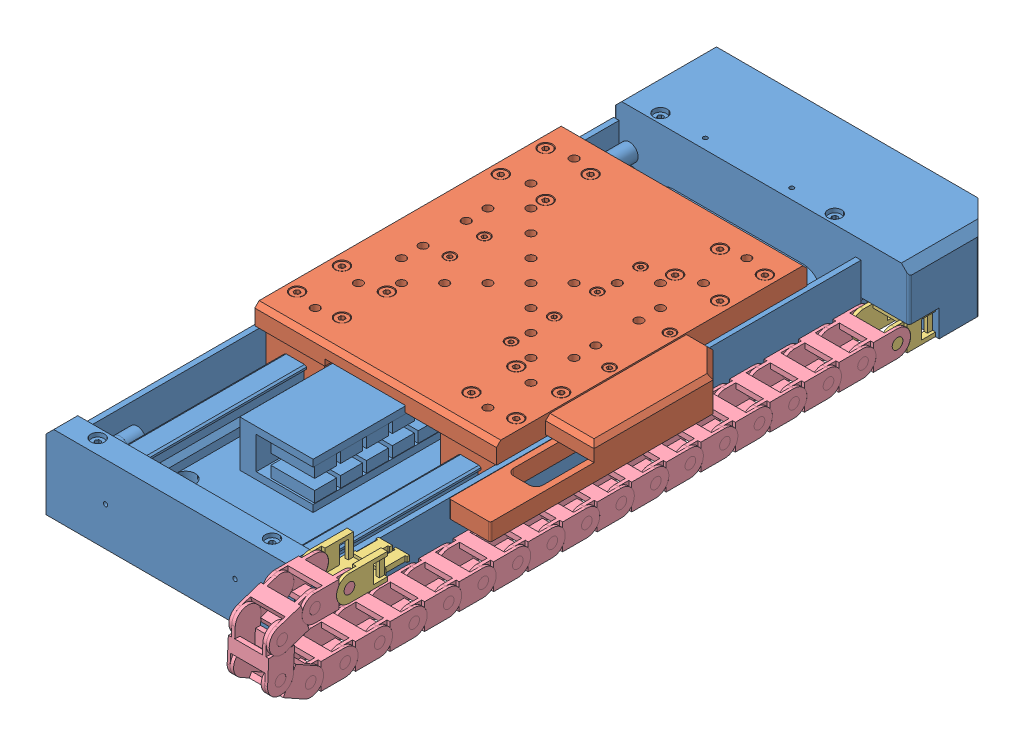
SolidWorks assembly LDQ, configuration LDQ0075C-AE53T10A. Lengths in mm.
Overall size (171 55.68 432.32).
26 component instances, 4 part files, 6 mates.
Components (placement in the parent):
- LDQ_base^LDQ-1: LDQ_base^LDQ [LDQ0075-T10A] at origin size (171 45.3 388.66) (virtual)
- LDQ_carriage^LDQ-1: LDQ_carriage^LDQ [Default] at (0 0 -37.5) size (168 31.5 211.5) (virtual)
- LDQ_cable^LDQ-1: LDQ_cable^LDQ [LDQ0075] at (85.6 44.8 164.95) size (23.4 55.68 389.66) (virtual)
  - LDQ_cable_end^LDQ_cable_LDQ-1: LDQ_cable_end^LDQ_cable_LDQ [bore] at origin size (23.4 15 45) (virtual)
  - LDQ_cable_end^LDQ_cable_LDQ-2: LDQ_cable_end^LDQ_cable_LDQ [pin] at (0 -36 -317.5) x (-1 0 0) z (0 0 1) size (23.4 15 29.5) (virtual)
  - LDQ_cable_link^LDQ_cable_LDQ-1: LDQ_cable_link^LDQ_cable_LDQ [Default] at (0 0 20) size (23.4 15 35) (virtual)
  - LDQ_cable_link^LDQ_cable_LDQ-27: LDQ_cable_link^LDQ_cable_LDQ [Default] at (0 -6.2457 38.9998) x (1 0 0) z (0 -0.312285 0.949989) size (23.4 15 35) (virtual)
  - LDQ_cable_link^LDQ_cable_LDQ-28: LDQ_cable_link^LDQ_cable_LDQ [Default] at (0 -26.2232 39.9475) x (1 0 0) z (0 -0.998877 0.047386) size (23.4 15 35) (virtual)
  - LDQ_cable_link^LDQ_cable_LDQ-29: LDQ_cable_link^LDQ_cable_LDQ [Default] at (0 -36 22.5) x (1 0 0) z (0 -0.488839 -0.872374) size (23.4 15 35) (virtual)
  - LDQ_cable_link^LDQ_cable_LDQ-31: LDQ_cable_link^LDQ_cable_LDQ [Default] at (0 -36 2.5) x (1 0 0) z (0 0 -1) size (23.4 15 35) (virtual)
  - LDQ_cable_link^LDQ_cable_LDQ-52: LDQ_cable_link^LDQ_cable_LDQ [Default] at (0 -36 -317.5) x (-1 0 0) z (0 0 -1) size (23.4 15 35) (virtual)
  - LDQ_cable_link^LDQ_cable_LDQ-53: LDQ_cable_link^LDQ_cable_LDQ [Default] at (0 -36 -297.5) x (-1 0 0) z (0 0 -1) size (23.4 15 35) (virtual)
  - LDQ_cable_link^LDQ_cable_LDQ-54: LDQ_cable_link^LDQ_cable_LDQ [Default] at (0 -36 -277.5) x (-1 0 0) z (0 0 -1) size (23.4 15 35) (virtual)
  - LDQ_cable_link^LDQ_cable_LDQ-55: LDQ_cable_link^LDQ_cable_LDQ [Default] at (0 -36 -257.5) x (-1 0 0) z (0 0 -1) size (23.4 15 35) (virtual)
  - LDQ_cable_link^LDQ_cable_LDQ-56: LDQ_cable_link^LDQ_cable_LDQ [Default] at (0 -36 -237.5) x (-1 0 0) z (0 0 -1) size (23.4 15 35) (virtual)
  - LDQ_cable_link^LDQ_cable_LDQ-57: LDQ_cable_link^LDQ_cable_LDQ [Default] at (0 -36 -217.5) x (-1 0 0) z (0 0 -1) size (23.4 15 35) (virtual)
  - LDQ_cable_link^LDQ_cable_LDQ-58: LDQ_cable_link^LDQ_cable_LDQ [Default] at (0 -36 -197.5) x (-1 0 0) z (0 0 -1) size (23.4 15 35) (virtual)
  - LDQ_cable_link^LDQ_cable_LDQ-59: LDQ_cable_link^LDQ_cable_LDQ [Default] at (0 -36 -177.5) x (-1 0 0) z (0 0 -1) size (23.4 15 35) (virtual)
  - LDQ_cable_link^LDQ_cable_LDQ-60: LDQ_cable_link^LDQ_cable_LDQ [Default] at (0 -36 -157.5) x (-1 0 0) z (0 0 -1) size (23.4 15 35) (virtual)
  - LDQ_cable_link^LDQ_cable_LDQ-61: LDQ_cable_link^LDQ_cable_LDQ [Default] at (0 -36 -137.5) x (-1 0 0) z (0 0 -1) size (23.4 15 35) (virtual)
  - LDQ_cable_link^LDQ_cable_LDQ-62: LDQ_cable_link^LDQ_cable_LDQ [Default] at (0 -36 -117.5) x (-1 0 0) z (0 0 -1) size (23.4 15 35) (virtual)
  - LDQ_cable_link^LDQ_cable_LDQ-63: LDQ_cable_link^LDQ_cable_LDQ [Default] at (0 -36 -97.5) x (-1 0 0) z (0 0 -1) size (23.4 15 35) (virtual)
  - LDQ_cable_link^LDQ_cable_LDQ-64: LDQ_cable_link^LDQ_cable_LDQ [Default] at (0 -36 -77.5) x (-1 0 0) z (0 0 -1) size (23.4 15 35) (virtual)
  - LDQ_cable_link^LDQ_cable_LDQ-65: LDQ_cable_link^LDQ_cable_LDQ [Default] at (0 -36 -57.5) x (-1 0 0) z (0 0 -1) size (23.4 15 35) (virtual)
  - LDQ_cable_link^LDQ_cable_LDQ-66: LDQ_cable_link^LDQ_cable_LDQ [Default] at (0 -36 -37.5) x (-1 0 0) z (0 0 -1) size (23.4 15 35) (virtual)
  - LDQ_cable_link^LDQ_cable_LDQ-67: LDQ_cable_link^LDQ_cable_LDQ [Default] at (0 -36 -17.5) x (-1 0 0) z (0 0 -1) size (23.4 15 35) (virtual)
Mates (geometry in assembly coordinates):
- Coincident1: coincident aligned: plane of LDQ_carriage^LDQ-1 through (0 0 -37.5) normal (1 0 0); plane of assembly through (0 0 0) normal (1 0 0)
- Coincident2: coincident aligned: plane of LDQ_carriage^LDQ-1 through (0 0 -37.5) normal (0 1 0); plane of assembly through (0 0 0) normal (0 1 0)
- LimitDistance1: limit distance = 0 mm aligned: plane of LDQ_carriage^LDQ-1 through (0 0 -37.5) normal (0 0 1); plane of LDQ_base^LDQ-1 through (0 0 -37.5) normal (0 0 1)
- Coincident4: coincident anti-aligned: plane of LDQ_base^LDQ-1 through (99 16.3 -157.55) normal (0 -1 0); plane of LDQ_cable^LDQ-1/LDQ_cable_end^LDQ_cable_LDQ-2 through (77.6 16.3 -152.55) normal (0 1 0)
- Distance2: distance = 5 mm aligned: plane of LDQ_cable^LDQ-1/LDQ_cable_end^LDQ_cable_LDQ-2 through (85.6 8.8 -152.55) normal (0 0 1); plane of LDQ_base^LDQ-1 through (-63.9 6.3 -157.55) normal (0 0 1)
- Distance3: distance = 85.6 mm aligned: plane of LDQ_cable^LDQ-1/LDQ_cable_end^LDQ_cable_LDQ-1 through (85.6 44.8 164.95) normal (1 0 0); plane of assembly through (0 0 0) normal (1 0 0)
